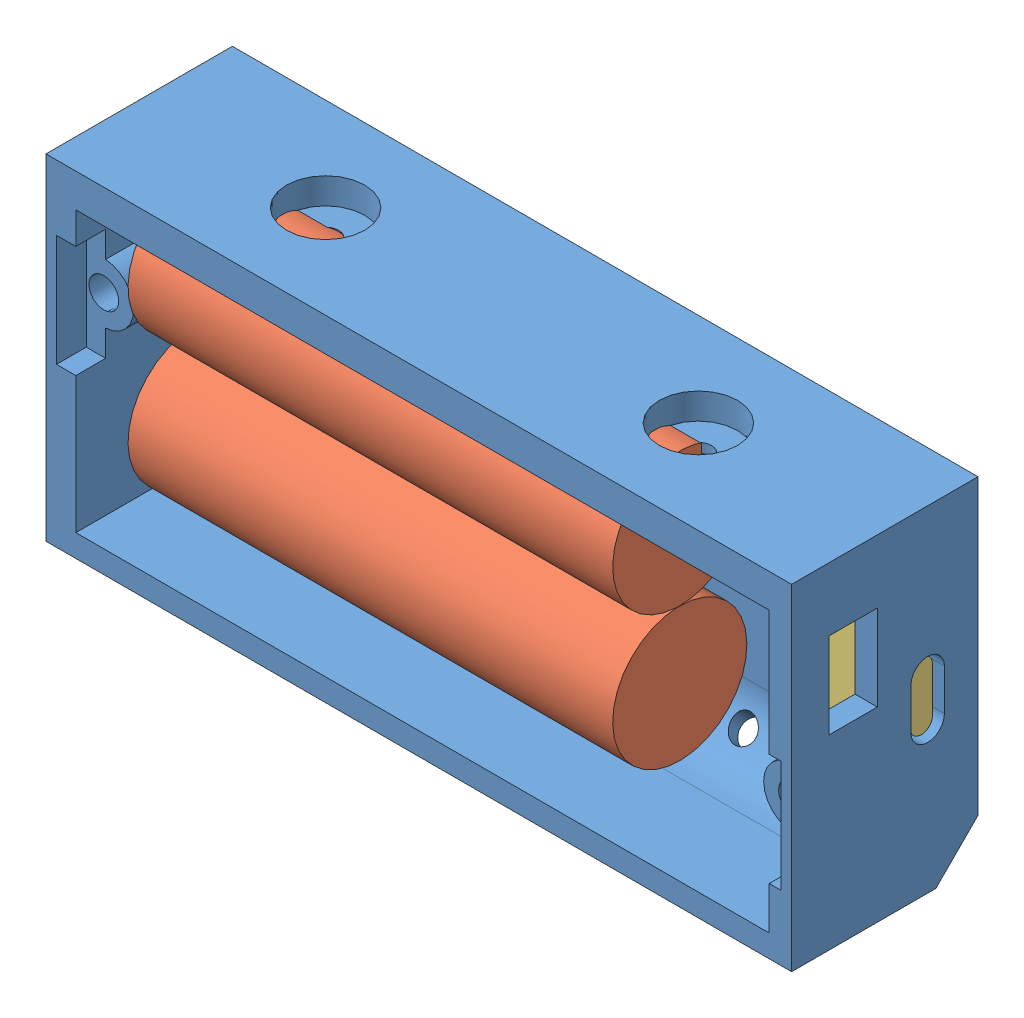
SolidWorks assembly Mont1, configuration Valor predeterminado. Lengths in mm.
Overall size (100 45.39 26.39).
4 component instances, 3 part files, 9 mates.
Components (placement in the parent):
- base-1: base [Valor predeterminado] at (-8.0678 2.2755 87.5) size (100 45 25)
- pilha 18650-1: pilha 18650 [Valor predeterminado] at (-49.0678 12.7755 101.5) x (0 -0.525341 0.850892) z (0 0.850892 0.525341) size (18 65 18)
- pilha 18650-2: pilha 18650 [Valor predeterminado] at (-49.0678 -5.2245 101.5) x (0 0.218815 -0.975766) z (0 -0.975766 -0.218815) size (18 65 18)
- DIY-charger-2: DIY-charger [Valor predeterminado] at (31.9322 0.1001 92.6) x (0 1 0) z (0 0 -1) size (15.5 17 4.6)
Mates (geometry in assembly coordinates):
- Tangente1: tangent anti-aligned: cylinder of pilha 18650-1 through (15.9322 12.7755 101.5) axis (1 0 0) radius 9; cylinder of pilha 18650-2 through (15.9322 -5.2245 101.5) axis (1 0 0) radius 9
- Coincidente1: coincident aligned: plane of pilha 18650-1 through (15.9322 8.0474 109.158) normal (1 0 0); plane of pilha 18650-2 through (15.9322 -3.2551 92.7181) normal (1 0 0)
- Tangente2: tangent anti-aligned: plane of base-1 through (-8.0678 2.2755 92.5) normal (0 0 1); cylinder of pilha 18650-2 through (15.9322 -5.2245 101.5) axis (1 0 0) radius 9
- Tangente3: tangent anti-aligned: plane of base-1 through (-8.0678 2.2755 92.5) normal (0 0 1); cylinder of pilha 18650-1 through (15.9322 12.7755 101.5) axis (1 0 0) radius 9
- Distância1: distance = 5 mm anti-aligned: plane of base-1 through (-54.0678 21.7755 112.5) normal (1 0 0); plane of pilha 18650-1 through (-49.0678 12.7755 101.5) normal (-1 0 0)
- Tangente5: tangent anti-aligned: plane of base-1 through (-54.0678 21.7755 112.5) normal (0 -1 0); cylinder of pilha 18650-1 through (15.9322 12.7755 101.5) axis (1 0 0) radius 9
- Coincidente3: coincident anti-aligned: plane of DIY-charger-2 through (31.9322 0.1001 91) normal (0 0 -1); plane of base-1 through (-8.0678 2.2755 91) normal (0 0 1)
- Paralelo2: parallel anti-aligned: plane of base-1 through (41.9322 24.7755 112.5) normal (1 0 0); plane of DIY-charger-2 through (33.9322 -0.8999 94.1) normal (-1 0 0)
- Coincidente5: coincident anti-aligned: plane of DIY-charger-2 through (39.9322 0.1001 91) normal (1 0 0); plane of base-1 through (39.9322 2.2755 98.5) normal (-1 0 0)
